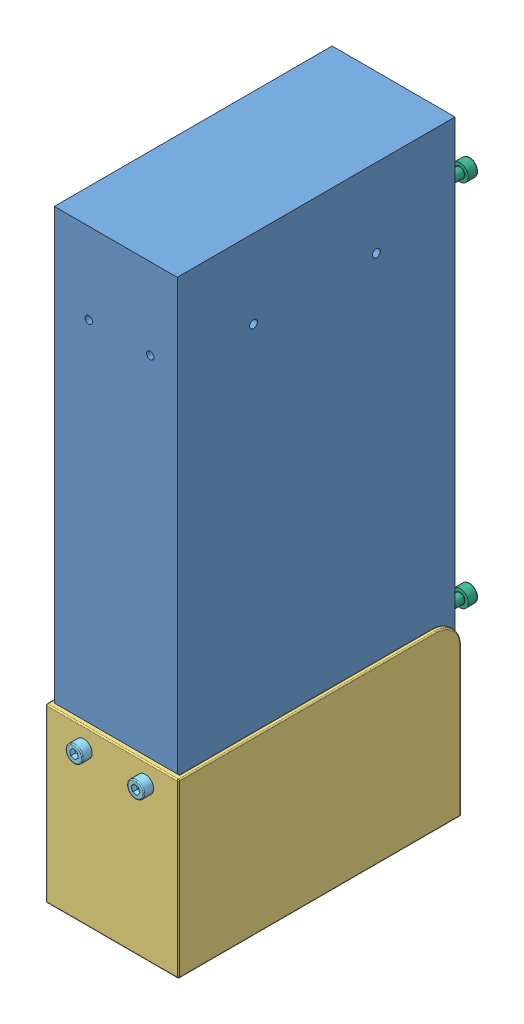
SolidWorks assembly ASM Power Supply, configuration Standard. Lengths in mm.
Overall size (65.46 245 137.01).
9 component instances, 6 part files, 21 mates.
Components (placement in the parent):
- 24V15A power supply-1: 24V15A power supply [Standard] at (53.5 109.5 7) x (0 -1 0) z (-1 0 0) size (215 113 50)
- power switch-1: power switch [Standard] x (0 0 -1) z (1 0 0) size (58.2 48.75 32.65)
- Power holder-1: Power holder [Standard] at (29 -28 8) x (0 0 1) z (0 1 0) size (115 56 70)
- M3X10 Flush Head Screw-1: M3X10 Flush Head Screw [Standard] at (-4.11 20 0) x (1 0 0) z (0 -0.753276 0.657705) size (10 5.54 5.54)
- M3X10 Flush Head Screw-2: M3X10 Flush Head Screw [Standard] at (-4.11 -20 0) x (1 0 0) z (0 -0.639466 0.768819) size (10 5.54 5.54)
- M4X8 Socket Head Screw-1: M4X8 Socket Head Screw [Standard] at (42.5 34 65.5) x (0 0 -1) z (0.779057 -0.626954 0) size (12 6.8 6.8)
- M4X8 Socket Head Screw-2: M4X8 Socket Head Screw [Standard] at (17.5 34 65.5) x (0 0 -1) z (0.669797 -0.742545 0) size (12 6.8 6.8)
- M4X20 Socket Head Screw-1: M4X20 Socket Head Screw [Standard] at (41.5 34.5 -63.5) x (0 0 1) z (-0.840178 -0.54231 0) size (24 6.8 6.8)
- M4X20 Socket Head Screw-2: M4X20 Socket Head Screw [Standard] at (41.5 184.5 -63.5) x (0 0 1) z (-0.915535 -0.402238 0) size (24 6.8 6.8)
Mates (geometry in assembly coordinates):
- Konzentrisch69: concentric anti-aligned: cylinder of power switch-1 through (-4 20 0) axis (1 0 0) radius 1.75; cylinder of Power holder-1 through (6 20 0) axis (-1 0 0) radius 1.3
- Konzentrisch70: concentric anti-aligned: cylinder of power switch-1 through (-4 -20 0) axis (1 0 0) radius 1.75; cylinder of Power holder-1 through (6 -20 0) axis (-1 0 0) radius 1.3
- Deckungsgleich81: coincident anti-aligned: plane of power switch-1 through (0 0 0) normal (1 0 0); plane of Power holder-1 through (0 -28 8) normal (-1 0 0)
- Konzentrisch84: concentric anti-aligned: cylinder of power switch-1 through (-4 20 0) axis (1 0 0) radius 1.75; cylinder of M3X10 Flush Head Screw-1 through (5.8907 20 0) axis (-1 0 0) radius 1.5293
- Deckungsgleich94: coincident aligned: cone of power switch-1 through (-4 20 0) axis (1 0 0); cone of M3X10 Flush Head Screw-1 through (-3.52 20 0) axis (1 0 0)
- Konzentrisch85: concentric anti-aligned: cylinder of power switch-1 through (-4 -20 0) axis (1 0 0) radius 1.75; cylinder of M3X10 Flush Head Screw-2 through (5.8907 -20 0) axis (-1 0 0) radius 1.5293
- Deckungsgleich95: coincident aligned: cone of power switch-1 through (-4 -20 0) axis (1 0 0); cone of M3X10 Flush Head Screw-2 through (-3.52 -20 0) axis (1 0 0)
- Konzentrisch71: concentric aligned: cylinder of 24V15A power supply-1 through (42.5 34 59.5) axis (0 0 1) radius 1.5; cylinder of Power holder-1 through (42.5 34 3.5) axis (0 0 1) radius 2.25
- Konzentrisch72: concentric aligned: cylinder of 24V15A power supply-1 through (17.5 34 59.5) axis (0 0 1) radius 1.5; cylinder of Power holder-1 through (17.5 34 3.5) axis (0 0 1) radius 2.25
- Deckungsgleich82: coincident anti-aligned: plane of 24V15A power supply-1 through (3.5 2 63.5) normal (0 0 1); plane of Power holder-1 through (2 42 63.5) normal (0 0 -1)
- Konzentrisch124: concentric aligned: cylinder of 24V15A power supply-1 through (41.5 34.5 -49.5) axis (0 0 -1) radius 1.65; cylinder of M4X20 Socket Head Screw-1 through (41.5 34.5 -64.4416) axis (0 0 -1) radius 2
- Konzentrisch125: concentric aligned: cylinder of 24V15A power supply-1 through (41.5 184.5 -49.5) axis (0 0 -1) radius 1.65; cylinder of M4X20 Socket Head Screw-2 through (41.5 184.5 -64.4416) axis (0 0 -1) radius 2
- Deckungsgleich96: coincident anti-aligned: plane of Power holder-1 through (2 42 65.5) normal (0 0 1); plane of M4X8 Socket Head Screw-1 through (44.6316 36.6488 65.5) normal (0 0 -1)
- Konzentrisch86: concentric aligned: cylinder of Power holder-1 through (42.5 34 3.5) axis (0 0 1) radius 2.25; cylinder of M4X8 Socket Head Screw-1 through (42.5 34 66.4416) axis (0 0 1) radius 2
- Deckungsgleich97: coincident anti-aligned: plane of Power holder-1 through (2 42 65.5) normal (0 0 1); plane of M4X8 Socket Head Screw-2 through (20.0247 36.2773 65.5) normal (0 0 -1)
- Konzentrisch87: concentric aligned: cylinder of Power holder-1 through (17.5 34 3.5) axis (0 0 1) radius 2.25; cylinder of M4X8 Socket Head Screw-2 through (17.5 34 66.4416) axis (0 0 1) radius 2
- Deckungsgleich98: coincident aligned: plane of M4X20 Socket Head Screw-1 through (39.6561 37.3566 -63.5) normal (0 0 1); plane of M4X20 Socket Head Screw-2 through (40.1324 187.6128 -63.5) normal (0 0 1)
- Abstand1: distance = 14 mm anti-aligned: plane of M4X20 Socket Head Screw-1 through (39.6561 37.3566 -63.5) normal (0 0 1); plane of 24V15A power supply-1 through (3.5 217 -49.5) normal (0 0 -1)
- Deckungsgleich99: coincident aligned: plane of power switch-1 through (0 0 0) normal (1 0 0); plane of assembly through (0 0 0) normal (1 0 0)
- Deckungsgleich100: coincident aligned: plane of power switch-1; plane of assembly through (0 0 0) normal (0 1 0)
- Deckungsgleich101: coincident anti-aligned: plane of power switch-1 through (0 0 0) normal (0 0 -1); plane of assembly through (0 0 0) normal (0 0 1)
